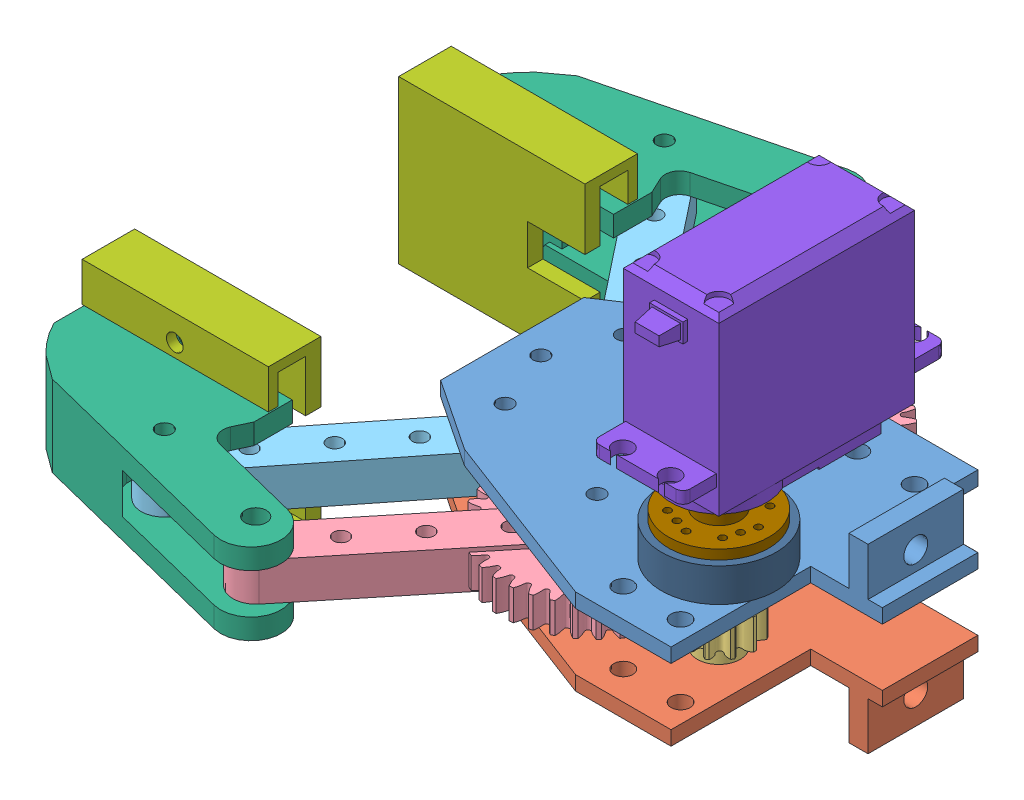
SolidWorks assembly gripper, configuration Default. Lengths in mm.
Overall size (138.92 83.67 149.98).
15 component instances, 10 part files, 31 mates.
Components (placement in the parent):
- Partx-1: Partx [Default] at (16.3665 50.5141 72.4661) size (87.5 13 64.26)
- Partx_2-1: Partx_2 [Default] at (16.3665 35.5141 72.4661) size (87.5 13 64.28)
- Part3_v2-1: Part3_v2 [GearTrax] at (61.3699 44.5141 92.5284) x (-0.689983 0 0.723825) z (0 -1 0) size (14.47 14.47 26.35)
- Part2-1: Part2 [GearTrax] at (35.8699 44.5141 54.0284) x (0.774957 0 -0.632013) z (0 1 0) size (40.13 75.63 8)
- part1-1: part1 [Default] at (-5.8832 44.5141 40.8536) x (0.784442 0 -0.620202) z (0.620202 0 0.784442) size (9.65 8 60.45)
- bar-1: bar [Default] at (-34.3364 53.0641 107.2583) x (1 0 0) z (0 -1 0) size (63.11 32.89 29)
- Part2-2: Part2 [GearTrax] at (35.8699 44.5141 92.5284) x (-0.774957 0 -0.632013) z (0 1 0) size (40.13 75.63 8)
- part1-2: part1 [Default] at (-5.8832 44.5141 105.7032) x (-0.784442 0 -0.620202) z (0.620202 0 -0.784442) size (9.65 8 60.45)
- bar-2: bar [Default] at (-34.3364 36.0641 39.2986) x (1 0 0) z (0 1 0) size (63.11 32.89 29)
- part8-1: part8 [Default] at (-13.5497 44.5641 40.1366) x (0 -1 0) z (0 0 -1) size (34 39 11)
- part8-2: part8 [Default] at (-13.5497 44.5641 106.4203) x (0 1 0) z (0 0 1) size (34 39 11)
- mg996r_plate-1: mg996r_plate [Default] at (11.1506 113.014 73.9243) x (0 0 1) z (1 0 0) size (55 47.5 26.36)
  - mg996r-1: mg996r [Default] at (8.1041 3.8249 50.2193) size (55 45.5 20)
  - rc plate-1: rc plate [Default] at (18.6041 51.3249 50.2193) x (-0.953412 0 0.301672) z (0.301672 0 0.953412) size (21 5 21)
- Partk-1: Partk [Default] at (61.3699 61.6891 92.5284) x (0.723825 0 0.689983) z (0.689983 0 -0.723825) size (24 7 24)
Mates (geometry in assembly coordinates):
- Concentric1: concentric: cylinder of assembly; cylinder of assembly; cylinder of Partx-1 through (35.8699 53.5141 54.0284) axis (0 -1 0) radius 1.65; cylinder of Part2-1 through (35.8699 48.5141 54.0284) axis (0 -1 0) radius 1.6
- Distance1: distance = 2 mm: plane of assembly; plane of assembly; plane of Partx-1 through (16.3665 50.5141 72.4661) normal (0 -1 0); plane of Part2-1 through (3.7636 48.5141 14.6606) normal (0 1 0)
- Concentric2: concentric: cylinder of assembly; cylinder of assembly; cylinder of Partx-1 through (35.8699 53.5141 92.5284) axis (0 -1 0) radius 1.65; cylinder of Part2-2 through (35.8699 48.5141 92.5284) axis (0 -1 0) radius 1.6
- Distance2: distance = 2 mm: plane of assembly; plane of assembly; plane of Partx-1 through (16.3665 50.5141 72.4661) normal (0 -1 0); plane of Part2-2 through (3.7636 48.5141 131.8963) normal (0 1 0)
- Concentric3: concentric: cylinder of assembly; cylinder of assembly; cylinder of Partx-1 through (61.3699 53.5141 92.5284) axis (0 -1 0) radius 3; cylinder of Part3_v2-1 through (61.3699 57.6891 92.5284) axis (0 -1 0) radius 4
- Coincident3: coincident: plane of assembly; plane of assembly; plane of Part3_v2-1 through (61.3699 41.3391 92.5284) normal (0 -1 0); plane of Part2-2 through (23.1612 41.3391 108.1115) normal (0 -1 0)
- Concentric4: concentric: cylinder of assembly; cylinder of assembly; cylinder of Partx-1 through (9.8699 53.5141 85.7784) axis (0 -1 0) radius 1.65; cylinder of part1-2 through (9.8699 48.5141 85.7784) axis (0 -1 0) radius 1.6
- Distance3: distance = 2 mm: plane of assembly; plane of assembly; plane of Partx-1 through (16.3665 50.5141 72.4661) normal (0 -1 0); plane of part1-2 through (-21.6364 48.5141 125.6281) normal (0 1 0)
- Concentric5: concentric: cylinder of assembly; cylinder of assembly; cylinder of Partx-1 through (9.8699 53.5141 60.7784) axis (0 -1 0) radius 1.65; cylinder of part1-1 through (9.8699 48.5141 60.7784) axis (0 -1 0) radius 1.6
- Distance4: distance = 2 mm: plane of assembly; plane of assembly; plane of Partx-1 through (16.3665 50.5141 72.4661) normal (0 -1 0); plane of part1-1 through (-21.6364 48.5141 20.9288) normal (0 1 0)
- Concentric6: concentric: cylinder of assembly; cylinder of assembly; cylinder of Part2-1 through (3.7636 48.5141 14.6606) axis (0 -1 0) radius 1.6; cylinder of bar-2 through (3.7636 53.0641 14.6606) axis (0 -1 0) radius 2.25
- Concentric7: concentric: cylinder of assembly; cylinder of assembly; cylinder of part1-1 through (-21.6364 48.5141 20.9288) axis (0 -1 0) radius 1.6; cylinder of bar-2 through (-21.6364 53.0641 20.9288) axis (0 -1 0) radius 1.65
- Distance5: distance = 0.15 mm: plane of assembly; plane of assembly; plane of bar-2 through (4.3264 40.3641 13.0992) normal (0 1 0); plane of Part2-1 through (3.7636 40.5141 14.6606) normal (0 -1 0)
- Concentric8: concentric: cylinder of assembly; cylinder of assembly; cylinder of bar-1 through (-21.6364 36.0641 125.6281) axis (0 1 0) radius 1.65; cylinder of part1-2 through (-21.6364 48.5141 125.6281) axis (0 -1 0) radius 1.6
- Concentric9: concentric: cylinder of assembly; cylinder of assembly; cylinder of bar-1 through (3.7636 36.0641 131.8963) axis (0 1 0) radius 2.25; cylinder of Part2-2 through (3.7636 48.5141 131.8963) axis (0 -1 0) radius 1.6
- Distance6: distance = 0.15 mm: plane of assembly; plane of assembly; plane of bar-1 through (4.3264 40.3641 133.4577) normal (0 1 0); plane of part1-2 through (-21.6364 40.5141 125.6281) normal (0 -1 0)
- Distance7: distance = 2 mm: plane of assembly; plane of assembly; plane of Partx_2-1 through (16.3665 38.5141 72.4661) normal (0 1 0); plane of Part2-2 through (3.7636 40.5141 131.8963) normal (0 -1 0)
- Concentric10: concentric: cylinder of assembly; cylinder of assembly; cylinder of Partx_2-1 through (61.3699 38.5141 92.5284) axis (0 -1 0) radius 3; cylinder of Part3_v2-1 through (61.3699 33.3391 92.5284) axis (0 1 0) radius 2.5
- Concentric11: concentric: cylinder of assembly; cylinder of assembly; cylinder of Partx_2-1 through (35.8699 38.5141 54.0284) axis (0 -1 0) radius 1.65; cylinder of Part2-1 through (35.8699 48.5141 54.0284) axis (0 -1 0) radius 1.6
- Coincident12: coincident: plane of assembly; plane of assembly; plane of bar-2 through (-42.993 59.0641 36.6366) normal (0 0 -1); plane of part8-1 through (-52.5497 44.5641 36.6366) normal (0 0 1)
- Coincident14: coincident: plane of assembly; plane of assembly; plane of bar-2 through (-13.5497 53.0641 31.6366) normal (1 0 0); plane of part8-1 through (-13.5497 44.5641 40.1366) normal (1 0 0)
- Distance9: distance = 0.5 mm: plane of assembly; plane of assembly; plane of part8-1 through (-52.5497 29.5641 40.1366) normal (0 1 0); plane of bar-2 through (-34.3364 30.0641 39.2986) normal (0 -1 0)
- Coincident16: coincident: plane of assembly; plane of assembly; plane of bar-1 through (-22.993 59.0641 109.9203) normal (0 0 1); plane of part8-2 through (-52.5497 44.5641 109.9203) normal (0 0 -1)
- Coincident17: coincident: plane of assembly; plane of assembly; plane of bar-1 through (-13.5497 36.0641 114.9203) normal (1 0 0); plane of part8-2 through (-13.5497 44.5641 106.4203) normal (1 0 0)
- Distance10: distance = 0.5 mm: plane of assembly; plane of assembly; plane of part8-2 through (-52.5497 29.5641 106.4203) normal (0 1 0); plane of bar-1 through (-34.3364 30.0641 107.2583) normal (0 -1 0)
- Coincident20: coincident: plane of assembly; plane of assembly; plane of bar-1 through (-52.4364 36.0641 114.9203) normal (-1 0 0); plane of bar-2 through (-52.4364 53.0641 31.6366) normal (-1 0 0)
- Coincident25: coincident: plane of assembly; plane of assembly; plane of Part3_v2-1 through (61.3699 59.6891 92.5284) normal (0 1 0); plane of Partk-1 through (61.3699 59.6891 92.5284) normal (0 -1 0)
- Concentric16: concentric: cylinder of assembly; cylinder of assembly; cylinder of mg996r_plate-1/rc plate-1 through (61.3699 60.6891 92.5284) axis (0 1 0) radius 1; cylinder of Partk-1 through (61.3699 61.6891 92.5284) axis (0 -1 0) radius 1.75
- Concentric19: concentric: cylinder of assembly; cylinder of assembly; cylinder of Part3_v2-1 through (61.3699 43.6891 92.5284) axis (0 1 0) radius 1.8; cylinder of Partk-1 through (61.3699 57.6891 92.5284) axis (0 -1 0) radius 4.15
- Coincident26: coincident: plane of assembly; plane of assembly; plane of mg996r_plate-1/rc plate-1 through (61.3699 61.6891 92.5284) normal (0 -1 0); plane of Partk-1 through (61.3699 61.6891 92.5284) normal (0 1 0)
- Parallel10: parallel: plane of assembly; plane of assembly; plane of Partx-1 through (79.3699 63.5141 83.2784) normal (-1 0 0); plane of mg996r_plate-1/mg996r-1 through (71.3699 69.1891 61.5284) normal (1 0 0)
